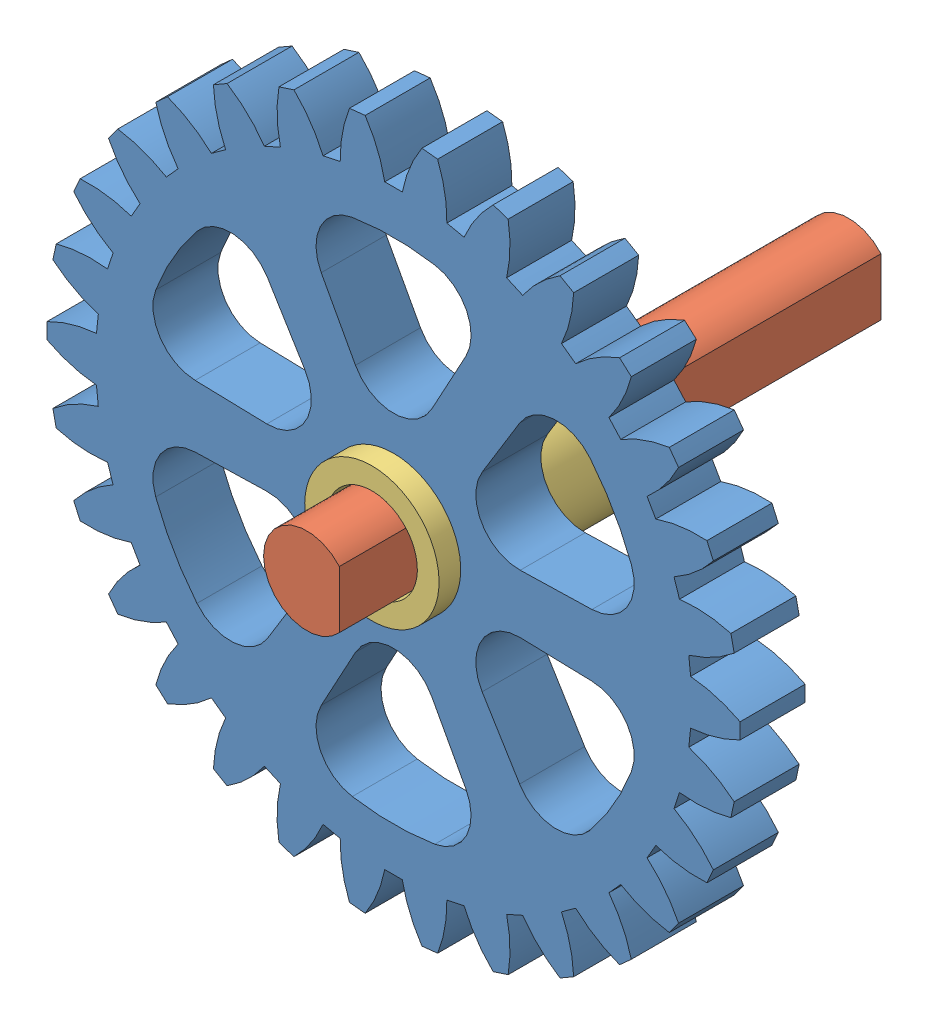
SolidWorks assembly Subassembly3, configuration Default. Lengths in mm.
Overall size (48 47.84 25).
4 component instances, 3 part files, 7 mates.
Components (placement in the parent):
- root gear assignment-1: root gear assignment [30T 1.5Mod] at (12.467 20.9936 19.8697) size (48 47.84 3)
- axle-1: axle [25mm axle] at (12.467 20.9936 1.8697) x (-1 0 0) z (0 0 1) size (3.5 4 25)
- Spacer-1: Spacer [4.2-1] at (12.467 20.9936 23.8697) x (-0.923728 -0.383049 0) z (0 0 -1) size (6.2 6.2 1)
- Spacer-2: Spacer [4.2-5] at (12.467 20.9936 14.8697) size (6.2 6.2 5)
Mates (geometry in assembly coordinates):
- Concentric1: concentric aligned: cylinder of root gear assignment-1 through (12.467 20.9936 22.8697) axis (0 0 -1) radius 2; cylinder of axle-1 through (12.467 20.9936 26.8697) axis (0 0 -1) radius 2
- Coincident1: coincident anti-aligned: plane of root gear assignment-1 through (13.967 22.3165 22.8697) normal (-1 0 0); plane of axle-1 through (13.967 19.6707 26.8697) normal (1 0 0)
- Coincident2: coincident anti-aligned: plane of root gear assignment-1 through (12.467 20.9936 22.8697) normal (0 0 1); plane of Spacer-1 through (12.467 20.9936 22.8697) normal (0 0 -1)
- Concentric2: concentric anti-aligned: cylinder of axle-1 through (12.467 20.9936 26.8697) axis (0 0 -1) radius 2; cylinder of Spacer-1 through (12.467 20.9936 22.8697) axis (0 0 1) radius 2.1
- Distance1: distance = 3 mm aligned: plane of Spacer-1 through (12.467 20.9936 23.8697) normal (0 0 1); plane of axle-1 through (12.467 20.9936 26.8697) normal (0 0 1)
- Concentric3: concentric aligned: cylinder of axle-1 through (12.467 20.9936 26.8697) axis (0 0 -1) radius 2; cylinder of Spacer-2 through (12.467 20.9936 19.8697) axis (0 0 -1) radius 2.1
- Coincident4: coincident anti-aligned: plane of root gear assignment-1 through (12.467 20.9936 19.8697) normal (0 0 -1); plane of Spacer-2 through (12.467 20.9936 19.8697) normal (0 0 1)
